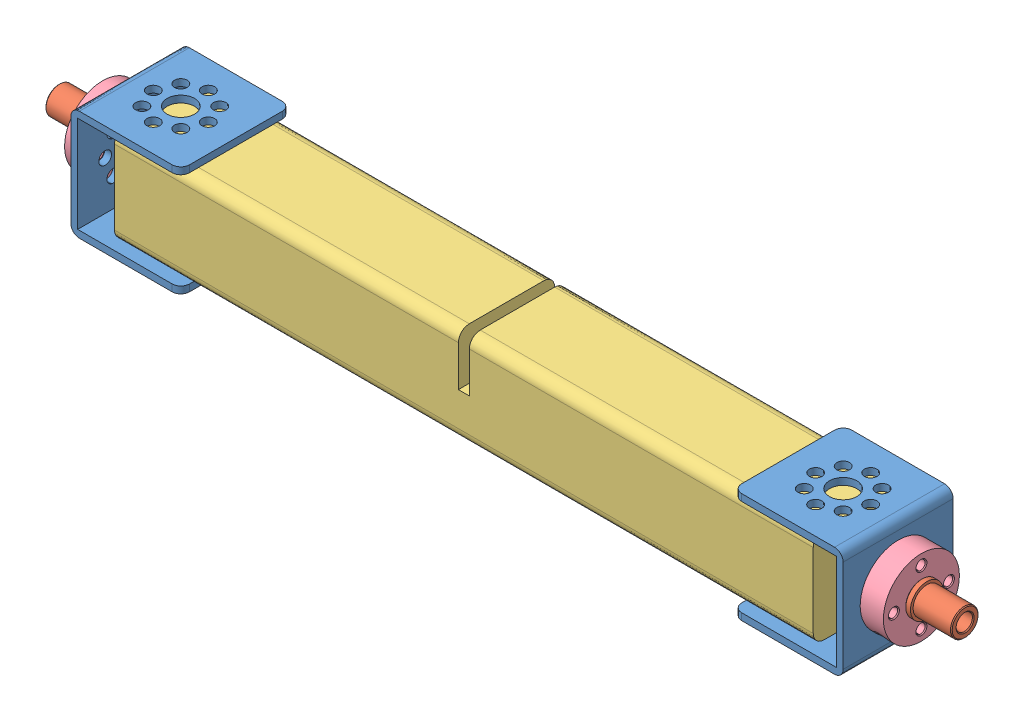
SolidWorks assembly Infeed Assembly, configuration Default. Lengths in mm.
Overall size (263.53 32 32).
11 component instances, 5 part files, 16 mates.
Components (placement in the parent):
- Tetrix Channel 32mm-2: Tetrix Channel 32mm [Default] at (17.5753 20.887 27.1898) x (0 -1 0) z (0 0 1) size (32 32 32)
- Tetrix Channel 32mm-3: Tetrix Channel 32mm [Default] at (242.1753 20.887 27.1898) x (0 1 0) z (0 0 1) size (32 32 32)
- Tetrix Bushing Bronze-1: Tetrix Bushing Bronze [Default] at (10.8253 20.887 27.1898) x (0 -0.535795 0.844348) z (0 -0.844348 -0.535795) size (9.56 12.71 9.56)
- Tetrix Bushing Bronze-2: Tetrix Bushing Bronze [Default] at (248.9253 20.887 27.1898) x (0 0.495751 0.868465) z (0 0.868465 -0.495751) size (9.56 12.71 9.56)
- Infeed Roller-1: Infeed Roller [Default] at (28.2753 20.887 27.1898) size (203.2 28 28)
- Tetrix Axle Hub-1: Tetrix Axle Hub [Default] at (17.5753 20.887 27.1898) x (0 0 1) z (1 0 0) size (22.1 22.1 9.5)
  - Tetrix Axle Hub Body-1: Tetrix Axle Hub Body [Default] at origin size (22.1 22.1 9.5)
  - Tetrix Axle Hub Set Screw-1: Tetrix Axle Hub Set Screw [Default] at (6.9308 6.9308 -3.325) x (-0.707107 0.707107 0) z (0 0 1) size (4.83 7.94 4.83)
- Tetrix Axle Hub-2: Tetrix Axle Hub [Default] at (242.1753 20.887 27.1898) x (0 -1 0) z (-1 0 0) size (22.1 22.1 9.5)
  - Tetrix Axle Hub Body-1: Tetrix Axle Hub Body [Default] at origin size (22.1 22.1 9.5)
  - Tetrix Axle Hub Set Screw-1: Tetrix Axle Hub Set Screw [Default] at (6.9308 6.9308 -3.325) x (-0.707107 0.707107 0) z (0 0 1) size (4.83 7.94 4.83)
Mates (geometry in assembly coordinates):
- Coincident4: coincident aligned: plane of Tetrix Channel 32mm-2 through (49.5753 36.887 11.1898) normal (0 1 0); plane of Tetrix Channel 32mm-3 through (242.1753 36.887 11.1898) normal (0 1 0)
- Coincident5: coincident: line of Tetrix Channel 32mm-2 through (47.0753 34.887 43.1898) axis (-1 0 0); plane of Tetrix Channel 32mm-3 through (242.1753 20.887 43.1898) normal (0 0 1)
- Coincident9: coincident anti-aligned: plane of Tetrix Channel 32mm-3 through (242.1753 4.887 11.1898) normal (1 0 0); plane of Tetrix Axle Hub-2/Tetrix Axle Hub Body-1 through (242.1753 20.887 27.1898) normal (-1 0 0)
- Concentric3: concentric aligned: cylinder of Tetrix Channel 32mm-3 through (240.1753 20.887 27.1898) axis (-1 0 0) radius 4; cylinder of Tetrix Axle Hub-2/Tetrix Axle Hub Body-1 through (242.1753 20.887 27.1898) axis (-1 0 0) radius 11.05
- Coincident10: coincident anti-aligned: plane of Tetrix Channel 32mm-2 through (17.5753 36.887 11.1898) normal (-1 0 0); plane of Tetrix Axle Hub-1/Tetrix Axle Hub Body-1 through (17.5753 20.887 27.1898) normal (1 0 0)
- Concentric4: concentric aligned: cylinder of Tetrix Channel 32mm-2 through (19.5753 20.887 27.1898) axis (1 0 0) radius 4; cylinder of Tetrix Axle Hub-1/Tetrix Axle Hub Body-1 through (17.5753 20.887 27.1898) axis (1 0 0) radius 11.05
- Concentric5: concentric anti-aligned: cylinder of Tetrix Channel 32mm-2 through (19.5753 20.887 19.1898) axis (1 0 0) radius 1.85; cylinder of Tetrix Axle Hub-1/Tetrix Axle Hub Body-1 through (10.8253 20.887 19.1898) axis (-1 0 0) radius 1.3525
- Concentric6: concentric anti-aligned: cylinder of Tetrix Channel 32mm-3 through (240.1753 20.887 19.1898) axis (-1 0 0) radius 1.85; cylinder of Tetrix Axle Hub-2/Tetrix Axle Hub Body-1 through (248.9253 20.887 19.1898) axis (1 0 0) radius 1.3525
- Concentric7: concentric aligned: cylinder of Tetrix Bushing Bronze-2 through (248.9253 20.887 27.1898) axis (-1 0 0) radius 4; cylinder of Tetrix Axle Hub-2/Tetrix Axle Hub Body-1 through (242.1753 20.887 27.1898) axis (-1 0 0) radius 11.05
- Coincident12: coincident anti-aligned: plane of Tetrix Bushing Bronze-2 through (248.9253 18.5173 23.0386) normal (-1 0 0); plane of Tetrix Axle Hub-2/Tetrix Axle Hub Body-1 through (248.9253 20.887 27.1898) normal (1 0 0)
- Concentric8: concentric aligned: cylinder of Tetrix Bushing Bronze-1 through (10.8253 20.887 27.1898) axis (1 0 0) radius 4; cylinder of Tetrix Axle Hub-1/Tetrix Axle Hub Body-1 through (17.5753 20.887 27.1898) axis (1 0 0) radius 11.05
- Coincident13: coincident anti-aligned: plane of Tetrix Bushing Bronze-1 through (10.8253 23.4481 23.1539) normal (1 0 0); plane of Tetrix Axle Hub-1/Tetrix Axle Hub Body-1 through (10.8253 20.887 27.1898) normal (-1 0 0)
- Coincident14: coincident anti-aligned: plane of Tetrix Channel 32mm-2 through (19.5753 34.887 11.1898) normal (0 -1 0); plane of Infeed Roller-1 through (231.4753 34.887 12.1898) normal (0 1 0)
- Distance4: distance = 2 mm aligned: plane of Tetrix Channel 32mm-2 through (17.5753 20.887 11.1898) normal (0 0 -1); plane of Infeed Roller-1 through (231.4753 6.887 13.1898) normal (0 0 -1)
- Distance5: distance = 241.3 mm anti-aligned: plane of Tetrix Bushing Bronze-2 through (250.5253 18.904 23.716) normal (1 0 0); plane of Tetrix Bushing Bronze-1 through (9.2253 23.0301 23.8124) normal (-1 0 0)
- Distance6: distance = 19.05 mm aligned: plane of Infeed Roller-1 through (28.2753 20.887 27.1898) normal (-1 0 0); plane of Tetrix Bushing Bronze-1 through (9.2253 23.0301 23.8124) normal (-1 0 0)
